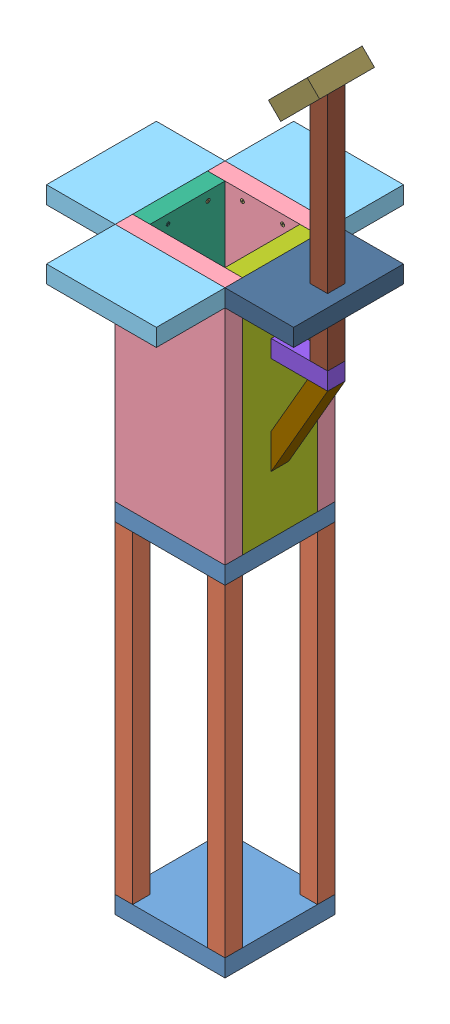
SolidWorks assembly 3U Drop tower holder, configuration Default. Lengths in mm.
Overall size (360 1155.64 360).
50 component instances, 12 part files, 33 mates.
Components (placement in the parent):
- Base tile-1: Base tile [Default] at origin size (160 25.4 160)
- helical holder-1: helical holder [Default] at (67.3 260.4 67.3) size (25.4 470 25.4)
- helical holder-2: helical holder [Default] at (-67.3 260.4 67.3) x (0 0 1) z (-1 0 0) size (25.4 470 25.4)
- helical holder-3: helical holder [Default] at (-67.3 260.4 -67.3) x (-1 0 0) z (0 0 -1) size (25.4 470 25.4)
- helical holder-4: helical holder [Default] at (67.3 260.4 -67.3) x (0 0 -1) z (1 0 0) size (25.4 470 25.4)
- Base tile-2: Base tile [top tile] at (0 520.8 0) x (-1 0 0) z (0 0 1) size (160 25.4 160)
- 90031A117_PHILLIPS FLAT HEAD SCREWS FOR WOOD-1: 90031A117_PHILLIPS FLAT HEAD SCREWS FOR WOOD [90031A117] at (-67.3 15.875 -67.3) x (0 1 0) z (-0.546944 0 0.837169) size (31.75 5.71 5.71)
- 90031A117_PHILLIPS FLAT HEAD SCREWS FOR WOOD-2: 90031A117_PHILLIPS FLAT HEAD SCREWS FOR WOOD [90031A117] at (67.3 15.875 -67.3) x (0 1 0) z (-0.837169 0 -0.546944) size (31.75 5.71 5.71)
- 90031A117_PHILLIPS FLAT HEAD SCREWS FOR WOOD-3: 90031A117_PHILLIPS FLAT HEAD SCREWS FOR WOOD [90031A117] at (67.3 15.875 67.3) x (0 1 0) z (0.546944 0 -0.837169) size (31.75 5.71 5.71)
- 90031A117_PHILLIPS FLAT HEAD SCREWS FOR WOOD-4: 90031A117_PHILLIPS FLAT HEAD SCREWS FOR WOOD [90031A117] at (-67.3 15.875 67.3) x (0 1 0) z (0.837169 0 0.546944) size (31.75 5.71 5.71)
- 90031A117_PHILLIPS FLAT HEAD SCREWS FOR WOOD-5: 90031A117_PHILLIPS FLAT HEAD SCREWS FOR WOOD [90031A117] at (-67.3 504.925 -67.3) x (0 -1 0) z (-0.546944 0 0.837169) size (31.75 5.71 5.71)
- 90031A117_PHILLIPS FLAT HEAD SCREWS FOR WOOD-6: 90031A117_PHILLIPS FLAT HEAD SCREWS FOR WOOD [90031A117] at (67.3 504.925 -67.3) x (0 -1 0) z (-0.837169 0 -0.546944) size (31.75 5.71 5.71)
- 90031A117_PHILLIPS FLAT HEAD SCREWS FOR WOOD-7: 90031A117_PHILLIPS FLAT HEAD SCREWS FOR WOOD [90031A117] at (67.3 504.925 67.3) x (0 -1 0) z (0.546944 0 -0.837169) size (31.75 5.71 5.71)
- 90031A117_PHILLIPS FLAT HEAD SCREWS FOR WOOD-8: 90031A117_PHILLIPS FLAT HEAD SCREWS FOR WOOD [90031A117] at (-67.3 504.925 67.3) x (0 -1 0) z (0.837169 0 0.546944) size (31.75 5.71 5.71)
- 90031A117_PHILLIPS FLAT HEAD SCREWS FOR WOOD-9: 90031A117_PHILLIPS FLAT HEAD SCREWS FOR WOOD [90031A117] at (67.3005 511.2241 29.2) x (0 1 0) z (0 0 1) size (31.75 5.71 5.71)
- 90031A117_PHILLIPS FLAT HEAD SCREWS FOR WOOD-10: 90031A117_PHILLIPS FLAT HEAD SCREWS FOR WOOD [90031A117] at (67.3005 511.2241 -29.2) x (0 1 0) z (0 0 1) size (31.75 5.71 5.71)
- 90031A117_PHILLIPS FLAT HEAD SCREWS FOR WOOD-11: 90031A117_PHILLIPS FLAT HEAD SCREWS FOR WOOD [90031A117] at (-67.3005 511.275 29.2) x (0 1 0) z (-0.546944 0 0.837169) size (31.75 5.71 5.71)
- 90031A117_PHILLIPS FLAT HEAD SCREWS FOR WOOD-12: 90031A117_PHILLIPS FLAT HEAD SCREWS FOR WOOD [90031A117] at (-67.3005 511.275 -29.2) x (0 1 0) z (-0.546944 0 0.837169) size (31.75 5.71 5.71) (hidden)
- long side-3: long side [Default] at (0 695.8 54.6) x (0 -1 0) z (-1 0 0) size (350 25.4 160)
- 90031A117_PHILLIPS FLAT HEAD SCREWS FOR WOOD-13: 90031A117_PHILLIPS FLAT HEAD SCREWS FOR WOOD [90031A117] at (29.2 511.275 67.3005) x (0 1 0) z (-0.546944 0 0.837169) size (31.75 5.71 5.71) (hidden)
- 90031A117_PHILLIPS FLAT HEAD SCREWS FOR WOOD-14: 90031A117_PHILLIPS FLAT HEAD SCREWS FOR WOOD [90031A117] at (-29.2 511.275 67.3005) x (0 1 0) z (-0.546944 0 0.837169) size (31.75 5.71 5.71) (hidden)
- long side-4: long side [Default] at (0 695.8 -54.6) x (0 -1 0) z (1 0 0) size (350 25.4 160)
- 90031A117_PHILLIPS FLAT HEAD SCREWS FOR WOOD-15: 90031A117_PHILLIPS FLAT HEAD SCREWS FOR WOOD [90031A117] at (29.2 511.275 -67.3005) x (0 1 0) z (-0.546944 0 0.837169) size (31.75 5.71 5.71)
- 90031A117_PHILLIPS FLAT HEAD SCREWS FOR WOOD-16: 90031A117_PHILLIPS FLAT HEAD SCREWS FOR WOOD [90031A117] at (-29.2 511.275 -67.3005) x (0 1 0) z (-0.546944 0 0.837169) size (31.75 5.71 5.71)
- antenna protector-1: antenna protector [Default] at (0 845.4 -130) x (0 0 1) z (-1 0 0) size (100 25.4 160)
- 90031A117_PHILLIPS FLAT HEAD SCREWS FOR WOOD-17: 90031A117_PHILLIPS FLAT HEAD SCREWS FOR WOOD [90031A117] at (-29.2 858.1 -70.475) x (0 0 -1) z (0.92358 0.383406 0) size (31.75 5.71 5.71)
- 90031A117_PHILLIPS FLAT HEAD SCREWS FOR WOOD-18: 90031A117_PHILLIPS FLAT HEAD SCREWS FOR WOOD [90031A117] at (29.2 858.1 -70.475) x (0 0 -1) z (0.92358 0.383406 0) size (31.75 5.71 5.71)
- antenna protector-2: antenna protector [Default] at (0 845.4 130) x (0 0 -1) z (1 0 0) size (100 25.4 160)
- 90031A117_PHILLIPS FLAT HEAD SCREWS FOR WOOD-19: 90031A117_PHILLIPS FLAT HEAD SCREWS FOR WOOD [90031A117] at (29.2 858.1 70.475) x (0 0 1) z (-0.923874 -0.382697 0) size (31.75 5.71 5.71)
- 90031A117_PHILLIPS FLAT HEAD SCREWS FOR WOOD-20: 90031A117_PHILLIPS FLAT HEAD SCREWS FOR WOOD [90031A117] at (-29.2 858.1 70.475) x (0 0 1) z (-0.923874 -0.382697 0) size (31.75 5.71 5.71)
- small side-1: small side [Default] at (-80 695.8 0) x (0 -1 0) z (0 0 1) size (350 25.4 109.2)
- 90031A117_PHILLIPS FLAT HEAD SCREWS FOR WOOD-21: 90031A117_PHILLIPS FLAT HEAD SCREWS FOR WOOD [90031A117] at (-67.3 858.1 -64.125) x (0 0 1) z (-1 0 0) size (31.75 5.71 5.71)
- 90031A117_PHILLIPS FLAT HEAD SCREWS FOR WOOD-22: 90031A117_PHILLIPS FLAT HEAD SCREWS FOR WOOD [90031A117] at (-67.3 858.1 64.125) x (0 0 -1) z (-1 0 0) size (31.75 5.71 5.71)
- 90031A117_PHILLIPS FLAT HEAD SCREWS FOR WOOD-23: 90031A117_PHILLIPS FLAT HEAD SCREWS FOR WOOD [90031A117] at (67.3 858.1 -64.125) x (0 0 1) z (-1 0 0) size (31.75 5.71 5.71)
- 90031A117_PHILLIPS FLAT HEAD SCREWS FOR WOOD-24: 90031A117_PHILLIPS FLAT HEAD SCREWS FOR WOOD [90031A117] at (67.3 858.1 64.125) x (0 0 -1) z (-1 0 0) size (31.75 5.71 5.71)
- antenna protector-3: antenna protector [Default] at (-130 845.4 0) size (100 25.4 160)
- 90031A117_PHILLIPS FLAT HEAD SCREWS FOR WOOD-27: 90031A117_PHILLIPS FLAT HEAD SCREWS FOR WOOD [90031A117] at (-78.6119 858.1 28.4) x (-1 0 0) z (0 -0.443974 -0.89604) size (31.75 5.71 5.71) (hidden)
- 90031A117_PHILLIPS FLAT HEAD SCREWS FOR WOOD-28: 90031A117_PHILLIPS FLAT HEAD SCREWS FOR WOOD [90031A117] at (-70.475 858.1 -30) x (-1 0 0) z (0 -0.322506 -0.946567) size (31.75 5.71 5.71)
- mounting-1: mounting [Default] at (-75.2195 780.2409 -235.0864) x (0 -1 0) z (0 0 1) size (634.84 125.4 160)
  - small side with mount-1: small side with mount [Default] at (84.4409 129.8195 235.0864) size (350 25.4 109.2)
  - a side of triangle-1: a side of triangle [Default] at (32.483 196.3149 235.0864) x (0 1 0) z (0 0 1) size (82.19 25.4 25.4)
  - hypothonuse-2: hypothonuse [Default] at (174.8409 155.2195 235.0864) x (0 0 1) z (0 -1 0) size (25.4 142.36 82.19)
  - antenna protector with mount-1: antenna protector with mount [Default] at (-90.5591 205.2195 235.0864) x (0 -1 0) z (0 0 1) size (100 25.4 160)
  - tall mount-1: tall mount [Default] at (-167.402 224.7099 235.0864) x (0 -1 0) z (0 0 -1) size (25.4 348.97 25.4)
  - mount top-1: mount top [Default] at (-329.154 224.6769 235.0844) x (0 0 1) z (0.707107 -0.707107 0) size (80 25.4 80)
  - 90031A117_PHILLIPS FLAT HEAD SCREWS FOR WOOD-1: 90031A117_PHILLIPS FLAT HEAD SCREWS FOR WOOD [90031A117] at (-335.8892 217.9417 235.0844) x (0.707107 0.707107 0) z (0 0 1) size (31.75 5.71 5.71)
  - 90031A117_PHILLIPS FLAT HEAD SCREWS FOR WOOD-2: 90031A117_PHILLIPS FLAT HEAD SCREWS FOR WOOD [90031A117] at (19.6301 145.6945 235.0326) x (0 1 0) z (-0.546944 0 0.837169) size (31.75 5.71 5.71)
  - 90031A117_PHILLIPS FLAT HEAD SCREWS FOR WOOD-3: 90031A117_PHILLIPS FLAT HEAD SCREWS FOR WOOD [90031A117] at (149.6575 145.6945 235.1226) x (0 1 0) z (-0.546944 0 0.837169) size (31.75 5.71 5.71)
  - 90031A117_PHILLIPS FLAT HEAD SCREWS FOR WOOD-6: 90031A117_PHILLIPS FLAT HEAD SCREWS FOR WOOD [90031A117] at (-77.8591 145.6945 264.2864) x (0 1 0) z (-0.546944 0 0.837169) size (31.75 5.71 5.71)
  - 90031A117_PHILLIPS FLAT HEAD SCREWS FOR WOOD-7: 90031A117_PHILLIPS FLAT HEAD SCREWS FOR WOOD [90031A117] at (-77.8591 145.6945 205.8864) x (0 1 0) z (-0.546944 0 0.837169) size (31.75 5.71 5.71)
Mates (geometry in assembly coordinates):
- Coincident1: coincident anti-aligned: plane of Base tile-1 through (0 25.4 0) normal (0 1 0); plane of helical holder-1 through (67.3 25.4 67.3) normal (0 -1 0)
- Concentric2: concentric aligned: cylinder of Base tile-1 through (67.3 0 67.3) axis (0 -1 0) radius 0.8065; cylinder of helical holder-1 through (67.3 25.4 67.3) axis (0 -1 0) radius 0.8065
- Coincident2: coincident anti-aligned: plane of helical holder-2 through (-67.3 495.4 67.3) normal (0 1 0); plane of Base tile-2 through (0 495.4 0) normal (0 -1 0)
- Concentric3: concentric aligned: circle of helical holder-3; circle of Base tile-2
- Concentric7: concentric aligned: cylinder of Base tile-2 through (67.3 520.8 -67.3) axis (0 1 0) radius 0.8065; cylinder of helical holder-4 through (67.3 495.4 -67.3) axis (0 1 0) radius 0.8065
- Concentric8: concentric aligned: circle of Base tile-1; cylinder of 90031A117_PHILLIPS FLAT HEAD SCREWS FOR WOOD-1 through (-67.3 0 -67.3) axis (0 -1 0) radius 1.4224
- Coincident6: coincident aligned: plane of Base tile-1 through (0 0 0) normal (0 -1 0); plane of 90031A117_PHILLIPS FLAT HEAD SCREWS FOR WOOD-1 through (-67.3 0 -67.3) normal (0 -1 0)
- Coincident12: coincident aligned: circle of Base tile-2; circle of 90031A117_PHILLIPS FLAT HEAD SCREWS FOR WOOD-13
- Coincident13: coincident anti-aligned: cone of Base tile-2 through (-29.2 495.4 67.3005) axis (0 1 0); circle of 90031A117_PHILLIPS FLAT HEAD SCREWS FOR WOOD-14
- Coincident16: coincident aligned: circle of Base tile-2; circle of 90031A117_PHILLIPS FLAT HEAD SCREWS FOR WOOD-16
- Coincident17: coincident anti-aligned: plane of long side-4 through (0 695.8 -80) normal (0 0 -1); plane of antenna protector-1 through (80 870.8 -80) normal (0 0 1)
- Coincident18: coincident aligned: circle of long side-4; circle of 90031A117_PHILLIPS FLAT HEAD SCREWS FOR WOOD-17
- Coincident19: coincident aligned: circle of long side-4; circle of 90031A117_PHILLIPS FLAT HEAD SCREWS FOR WOOD-18
- Coincident20: coincident aligned: circle of long side-3; circle of 90031A117_PHILLIPS FLAT HEAD SCREWS FOR WOOD-19
- Coincident21: coincident aligned: circle of long side-3; circle of 90031A117_PHILLIPS FLAT HEAD SCREWS FOR WOOD-20
- Coincident30: coincident aligned: circle of long side-4; circle of 90031A117_PHILLIPS FLAT HEAD SCREWS FOR WOOD-21
- Coincident31: coincident aligned: circle of long side-4; circle of 90031A117_PHILLIPS FLAT HEAD SCREWS FOR WOOD-23
- Concentric24: concentric aligned: circle of small side-1; circle of 90031A117_PHILLIPS FLAT HEAD SCREWS FOR WOOD-27
- Concentric25: concentric aligned: circle of small side-1; circle of 90031A117_PHILLIPS FLAT HEAD SCREWS FOR WOOD-27
- Concentric26: concentric aligned: circle of small side-1; circle of 90031A117_PHILLIPS FLAT HEAD SCREWS FOR WOOD-28
- Coincident47: coincident aligned: plane of long side-4 through (-80 870.8 -80) normal (0 1 0); plane of antenna protector-1 through (0 870.8 -130) normal (0 1 0)
- Coincident48: coincident aligned: plane of long side-4 through (-80 870.8 -80) normal (-1 0 0); plane of antenna protector-1 through (-80 870.8 -180) normal (-1 0 0)
- Concentric29: concentric aligned: cylinder of small side-1 through (-54.6 858.1 28.4) axis (1 0 0) radius 0.889; cylinder of antenna protector-3 through (-80 858.1 28.4) axis (1 0 0) radius 0.889
- Coincident57: coincident anti-aligned: plane of Base tile-2 through (0 520.8 0) normal (0 1 0); plane of long side-3 through (80 520.8 80) normal (0 -1 0)
- Coincident61: coincident aligned: plane of long side-3 through (-80 870.8 80) normal (-1 0 0); plane of Base tile-2 through (-80 495.4 80) normal (-1 0 0)
- Coincident62: coincident aligned: plane of Base tile-2 through (80 495.4 80) normal (0 0 1); plane of long side-3 through (0 695.8 80) normal (0 0 1)
- Coincident68: coincident aligned: plane of small side-1 through (-54.6 870.8 -54.6) normal (0 1 0); plane of antenna protector-3 through (-130 870.8 0) normal (0 1 0)
- Coincident70: coincident anti-aligned: plane of long side-4 through (-80 870.8 -80) normal (-1 0 0); plane of antenna protector-3 through (-80 870.8 -80) normal (1 0 0)
- Coincident71: coincident aligned: circle of small side-1; plane of 90031A117_PHILLIPS FLAT HEAD SCREWS FOR WOOD-28 through (-54.6 858.1 -30) normal (1 0 0)
- Coincident72: coincident anti-aligned: plane of long side-4 through (0 695.8 -54.6) normal (0 0 1); plane of small side-1 through (-54.6 870.8 -54.6) normal (0 0 -1)
- Coincident73: coincident aligned: line of Base tile-2 through (-80 520.8 80) axis (0 0 -1); line of small side-1 through (-80 520.8 54.6) axis (0 0 -1)
- Coincident74: coincident anti-aligned: line of Base tile-2 through (80 520.8 -80) axis (0 0 1); line of mounting-1/small side with mount-1 through (80 520.8 54.6) axis (0 0 -1)
- Coincident75: coincident anti-aligned: line of long side-3 through (80 520.8 54.6) axis (0 1 0); line of mounting-1/small side with mount-1 through (80 870.8 54.6) axis (0 -1 0)
